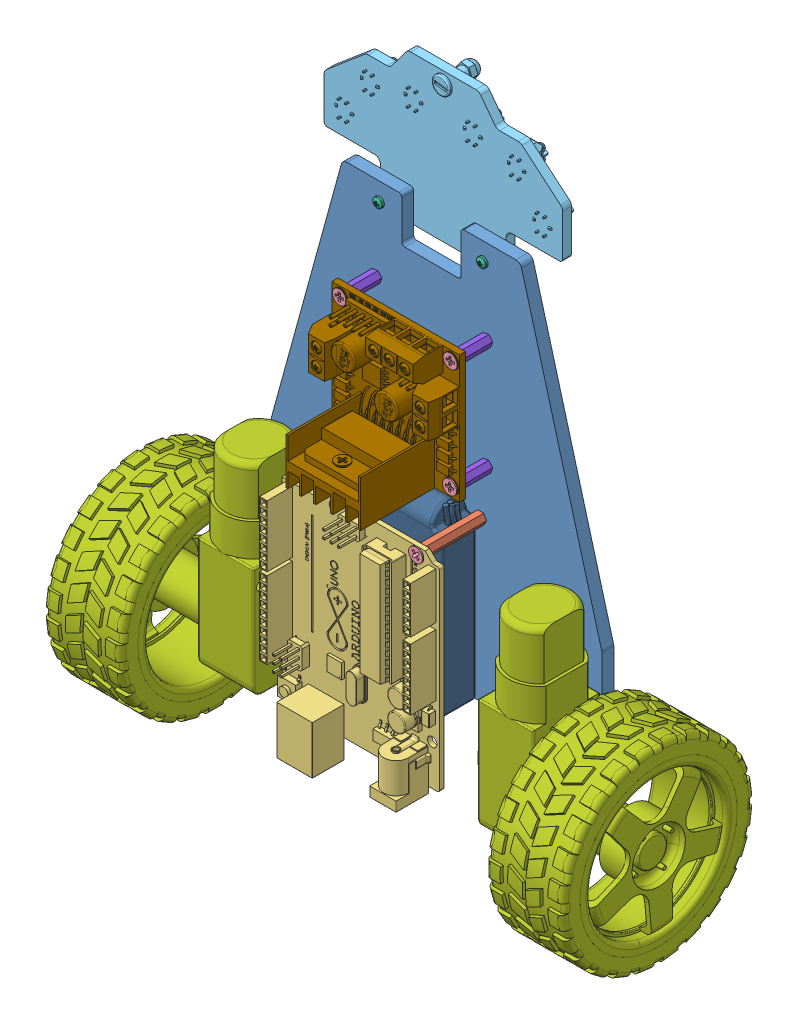
SolidWorks assembly Assem1, configuration Default. Lengths in mm.
Overall size (175.42 217.56 91.61).
22 component instances, 10 part files, 3 mates.
Components (placement in the parent):
- LF GUA-1: LF GUA [Default] at (29.1127 23.3617 40.9372) size (175.42 217.56 91.61)
  - base plat-1: base plat [Default] at (61.7935 8.952 136.5632) size (115 150 4)
  - spacer 20 mm-1: spacer 20 mm [Default] at (20.8935 77.752 140.5632) x (0.672008 -0.740544 0) z (0 0 -1) size (3.93 3.83 24)
  - spacer 20 mm-2: spacer 20 mm [Default] at (-22.2065 26.952 140.5632) x (0.817546 -0.575863 0) z (0 0 -1) size (3.93 3.83 24)
  - Arduino UNO-1: Arduino UNO [Default] at (-66.2315 48.46 160.3492) x (0 1 0) z (1 0 0) size (74.8 15.3 53.05)
  - srcrew-1: srcrew [Default] at (-22.2065 26.952 162.5132) x (0 0 -1) z (0.969792 0.243933 0) size (3 4.7 4.7)
  - srcrew-2: srcrew [Default] at (20.8935 77.752 162.5132) x (0 0 -1) z (0.721324 -0.692598 0) size (3 4.7 4.7)
  - sensor TCRT5000-1: sensor TCRT5000 [Default] at (18.7348 128.8233 200.7685) x (-1 0 0) z (0 0 -1) size (80.4 50 12.51)
  - baut-1: baut [Default] at (-13.2065 152.952 141.8632) x (0 0 -1) z (1 0 0) size (5.27 3.2 3.2)
  - baut-2: baut [Default] at (21.7935 152.952 141.8632) x (0 0 -1) z (1 0 0) size (5.27 3.2 3.2)
  - dc_motor_and_wheel-1: dc_motor_and_wheel [Default] at (-61.0285 -32.372 143.0932) x (-1 0 0) z (0 0.96637 0.257157) size (59.31 65 88.5)
  - dc_motor_and_wheel-2: dc_motor_and_wheel [Default] at (70.2155 -32.372 160.5332) x (1 0 0) z (0 0.96637 -0.257157) size (59.31 65 88.5)
  - spacer 2.5 mm-1: spacer 2.5 mm [Default] at (22.9835 93.952 140.5632) x (-0.923728 -0.383049 0) z (0 0 -1) size (3.93 3.83 14)
  - spacer 2.5 mm-2: spacer 2.5 mm [Default] at (22.9835 130.692 140.5632) x (-0.923728 -0.383049 0) z (0 0 -1) size (3.93 3.83 14)
  - spacer 2.5 mm-3: spacer 2.5 mm [Default] at (-14.3965 130.692 140.5632) x (-0.923728 -0.383049 0) z (0 0 -1) size (3.93 3.83 14)
  - spacer 2.5 mm-4: spacer 2.5 mm [Default] at (-14.3965 93.952 140.5632) x (-0.923728 -0.383049 0) z (0 0 -1) size (3.93 3.83 14)
  - L298N-1: L298N [Default] at (-85.1502 63.6285 163.8582) x (-1 0.000031 0) z (0.000031 1 0) size (43 28.01 43)
  - srcrew-3: srcrew [Default] at (-14.396 130.6932 152.9632) x (0 0 -1) z (1 0 0) size (3 4.7 4.7)
  - srcrew-4: srcrew [Default] at (22.9835 130.692 152.9632) x (0 0 -1) z (1 0 0) size (3 4.7 4.7)
  - srcrew-5: srcrew [Default] at (-14.3972 93.9514 153.1632) x (0 0 -1) z (1 0 0) size (3 4.7 4.7)
  - srcrew-6: srcrew [Default] at (22.9823 93.9502 153.1632) x (0 0 -1) z (1 0 0) size (3 4.7 4.7)
- LiPo - Zippy Compact 350-1: LiPo - Zippy Compact 350 [Default] at (33.4062 77.3137 181.5004) x (0 1 0) z (1 0 0) size (60.31 12 30.5)
Mates (geometry in assembly coordinates):
- Coincident1: coincident: plane of LF GUA-1/base plat-1 through (90.9062 32.3137 181.5004) normal (0 0 1); plane of LiPo - Zippy Compact 350-1 through (33.4062 77.3137 181.5004) normal (0 0 -1)
- Coincident2: coincident: plane of LF GUA-1/base plat-1 through (-4.0938 47.3137 177.5004) normal (0 -1 0); plane of LiPo - Zippy Compact 350-1 through (18.1562 47.3137 193.5004) normal (0 -1 0)
- Width1: width anti-aligned: plane of LiPo - Zippy Compact 350-1 through (18.1562 47.3137 193.5004) normal (-1 0 0); plane of LiPo - Zippy Compact 350-1 through (48.6562 47.3137 193.5004) normal (1 0 0); plane of LF GUA-1/base plat-1 through (90.9062 32.3137 181.5004) normal (1 0 0); plane of LF GUA-1/base plat-1 through (-24.0938 32.3137 181.5004) normal (-1 0 0)
